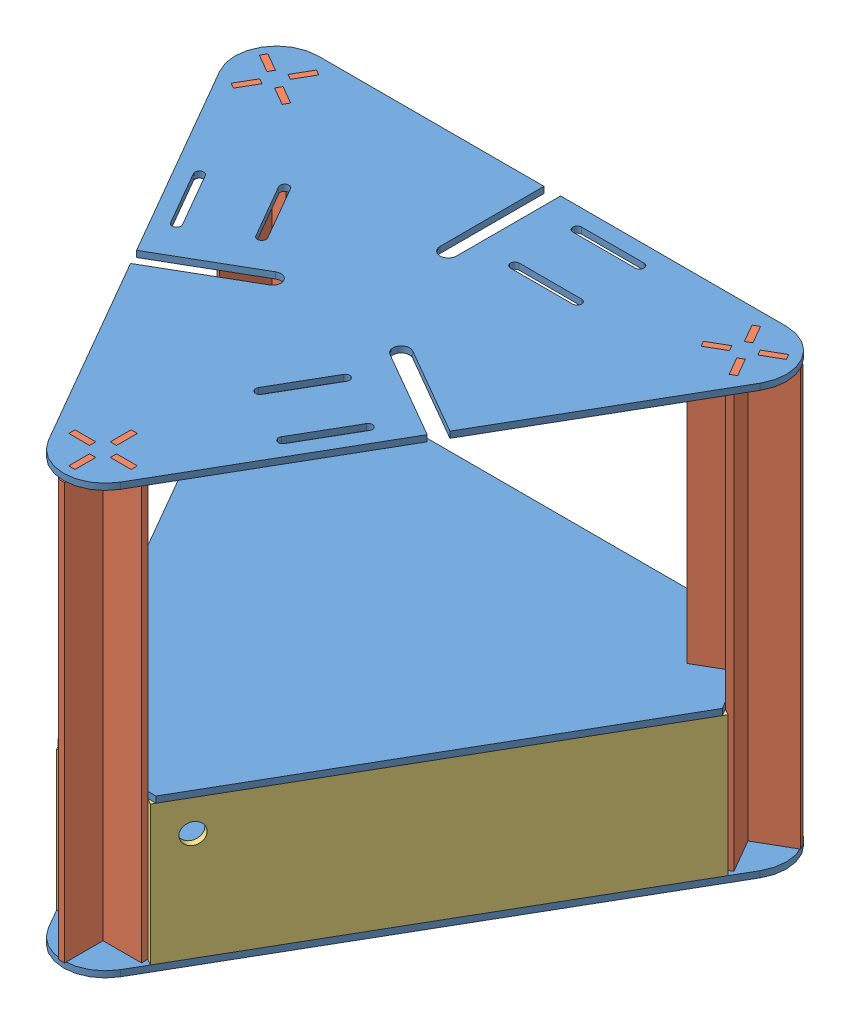
SolidWorks assembly Estructura Robot Delta, configuration Predeterminado. Lengths in mm.
Overall size (336.1 206 347.14).
16 component instances, 4 part files, 20 mates.
Components (placement in the parent):
- Base-4: Base [Base Superior] at (0 201.5 0) x (1 0 0) z (0 0 -1) size (265.17 3 235)
- Pata-1: Pata [Predeterminado] at (-3.0521 78.0313 130.6393) size (40 206 40)
  - Pata-1: Pata [conf2] at (2.6829 -78.0313 0) size (3 206 40)
  - Pata-2: Pata [conf1] at (2.6829 -78.0313 0) x (0 0 -1) z (1 0 0) size (3 206 40)
- Pieza1^Estructura Robot Delta-1: Pieza1^Estructura Robot Delta [Predeterminado] at origin (virtual)
- Base-5: Base [Base Inferior] at (0 -1.5 0) x (0.5 0 -0.866025) z (0.866025 0 0.5) size (265.17 3 235)
- Pata-4: Pata [Predeterminado] at (110.2598 78.0313 -63.6585) x (0.866025 0 -0.5) z (0.5 0 0.866025) size (40 206 40)
  - Pata-1: Pata [conf2] at (2.6829 -78.0313 0) size (3 206 40)
  - Pata-2: Pata [conf1] at (2.6829 -78.0313 0) x (0 0 -1) z (1 0 0) size (3 206 40)
- Pata-5: Pata [Predeterminado] at (-114.663 78.0313 -62.6765) x (0.5 0 -0.866025) z (0.866025 0 0.5) size (40 206 40)
  - Pata-1: Pata [conf2] at (2.6829 -78.0313 0) size (3 206 40)
  - Pata-2: Pata [conf1] at (2.6829 -78.0313 0) x (0 0 -1) z (1 0 0) size (3 206 40)
- Base-6: Base [base intermedia] at (0 68.5 0) x (1 0 0) z (0 0 -1) size (246.9 3 214.14)
- Pared-1: Pared [Predeterminado] at (73.4268 33.5 42.8211) x (0.5 0 -0.866025) z (0.866025 0 0.5) size (203.31 67 3)
- Pared-2: Pared [Predeterminado] at (0.1767 33.5 -85) x (-1 0 0) z (0 0 -1) size (203.31 67 3)
- Pared-3: Pared [trasera] at (-73.613 33.5 42.4986) x (0.5 0 0.866025) z (-0.866025 0 0.5) size (203.31 67 3)
Mates (geometry in assembly coordinates):
- Coincidente2: coincident anti-aligned: plane of Base-4 through (0 201.5 0) normal (0 0 -1)
- Coincidente3: coincident aligned: plane of Base-4 through (0 201.5 0) normal (1 0 0)
- Coincidente4: coincident aligned: line of Base-4 through (-1.8691 203 115.6393) axis (0 0 1); line of Pata-1/Pata-1 through (-1.8691 203 115.6393) axis (0 0 1)
- Coincidente5: coincident aligned: line of Base-4 through (-15.3691 203 132.1393) axis (1 0 0); line of Pata-1/Pata-2 through (-15.3691 203 132.1393) axis (1 0 0)
- Coincidente9: coincident anti-aligned: line of Pata-1/Pata-1 through (1.1309 -3 145.6393) axis (0 0 -1); line of Base-5 through (1.1309 -3 135.6393) axis (0 0 1)
- Coincidente10: coincident anti-aligned: line of Pata-1/Pata-1 through (1.1309 -3 135.6393) axis (-1 0 0); line of Base-5 through (-1.8691 -3 135.6393) axis (1 0 0)
- Coincidente11: coincident aligned: plane of Base-5 through (0 0 130) normal (0 1 0)
- Coincidente12: coincident aligned: line of Base-4 through (98.8429 203 -58.799) axis (0.5 0 0.866025); line of Pata-4/Pata-2 through (98.8429 203 -58.799) axis (0.5 0 0.866025)
- Coincidente13: coincident aligned: line of Base-4 through (106.3823 203 -78.7404) axis (-0.866025 0 0.5); line of Pata-4/Pata-1 through (106.3823 203 -78.7404) axis (-0.866025 0 0.5)
- Coincidente14: coincident anti-aligned: line of Base-4 through (-101.0812 203 -56.201) axis (0.5 0 -0.866025); line of Pata-5/Pata-1 through (-99.5812 203 -58.799) axis (-0.5 0 0.866025)
- Coincidente15: coincident aligned: line of Base-4 through (-122.1206 203 -52.7596) axis (0.866025 0 0.5); line of Pata-5/Pata-2 through (-122.1206 203 -52.7596) axis (0.866025 0 0.5)
- Coincidente16: coincident aligned: plane of Base-4 through (0 201.5 0) normal (1 0 0); plane of Base-6 through (0 68.5 0) normal (1 0 0)
- Coincidente18: coincident aligned: plane of Base-4 through (0 201.5 0) normal (0 0 -1); plane of Base-6 through (0 68.5 0) normal (0 0 -1)
- Distancia1: distance = 130 mm anti-aligned: plane of Base-6 through (-112.5833 70 -65) normal (0 1 0); plane of Base-4 through (-112.5833 200 -65) normal (0 -1 0)
- Coincidente22: coincident aligned: plane of Base-6 through (17.3205 67 140) normal (0.866025 0 0.5); plane of Pared-1 through (73.4268 33.5 42.8211) normal (0.866025 0 0.5)
- Coincidente21: coincident anti-aligned: plane of Base-5 through (0 0 130) normal (0 1 0); plane of Pared-1 through (20.0012 0 129.3569) normal (0 -1 0)
- Coincidente23: coincident: line of Pata-4/Pata-1 through (121.2843 200 -46.9295) axis (0 -1 0); plane of Pared-1 through (121.6562 0 -46.7147) normal (0.5 0 -0.866025)
- Coincidente24: coincident aligned: plane of Base-6 through (-129.9038 67 -55) normal (-0.866025 0 0.5); plane of Pared-3 through (-73.613 33.5 42.4986) normal (-0.866025 0 0.5)
- Coincidente25: coincident: plane of Base-5 through (0 0 130) normal (0 1 0); line of Pared-3 through (-124.4405 0 -45.5372) axis (0.5 0 0.866025)
- Coincidente26: coincident: line of Pata-1/Pata-2 through (-20.3691 0 129.1393) axis (0 1 0); plane of Pared-3 through (-20.1874 0 129.0344) normal (0.5 0 0.866025)
